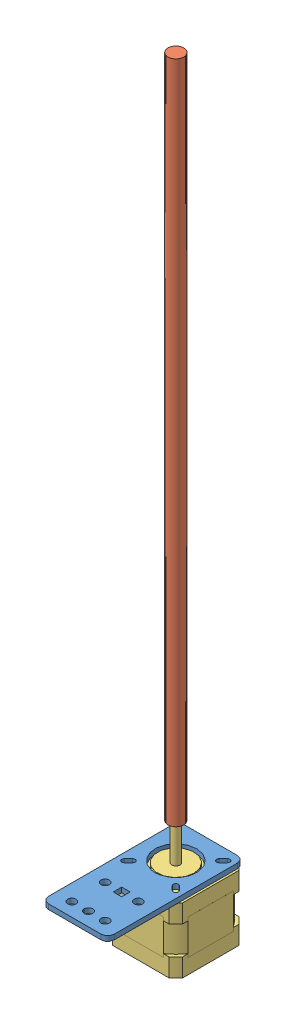
SolidWorks assembly Acme rod stepper assy, configuration Default. Lengths in mm.
Overall size (42.02 463.12 82.75).
3 component instances, 3 part files, 5 mates.
Components (placement in the parent):
- Motor Mount Plate Nema 17-1: Motor Mount Plate Nema 17 [Default] at (45.3649 37.3202 58.8727) size (39.5 3 82)
- threaded rod-1: threaded rod [400mm] at (45.3649 61.3202 58.8727) size (9.53 400 9.53)
- STEPPER-1: STEPPER [Default] at (45.3649 -1.7958 58.8727) x (1 0 0) z (0 1 0) size (42.02 53.01 63.12)
Mates (geometry in assembly coordinates):
- Concentric1: concentric: cylinder of Motor Mount Plate Nema 17-1 through (45.3649 40.3202 58.8727) axis (0 -1 0) radius 12.5; cylinder of STEPPER-1 through (45.3649 37.3202 58.8727) axis (0 1 0) radius 11
- Coincident1: coincident: plane of Motor Mount Plate Nema 17-1 through (29.6149 37.3202 115.6227) normal (0 -1 0); plane of STEPPER-1 through (45.3649 37.3202 58.8727) normal (0 1 0)
- Parallel1: parallel aligned: plane of Motor Mount Plate Nema 17-1 through (65.1149 40.3202 115.6227) normal (1 0 0); plane of STEPPER-1 through (66.3649 28.3202 75.8433) normal (1 0 0)
- Concentric2: concentric: cylinder of threaded rod-1 through (45.3649 461.3202 58.8727) axis (0 -1 0) radius 4.7625; cylinder of STEPPER-1 through (45.3649 39.3202 58.8727) axis (0 1 0) radius 2.5
- Coincident3: coincident anti-aligned: plane of threaded rod-1 through (45.3649 61.3202 58.8727) normal (0 -1 0); plane of STEPPER-1 through (45.3649 61.3202 58.8727) normal (0 1 0)
